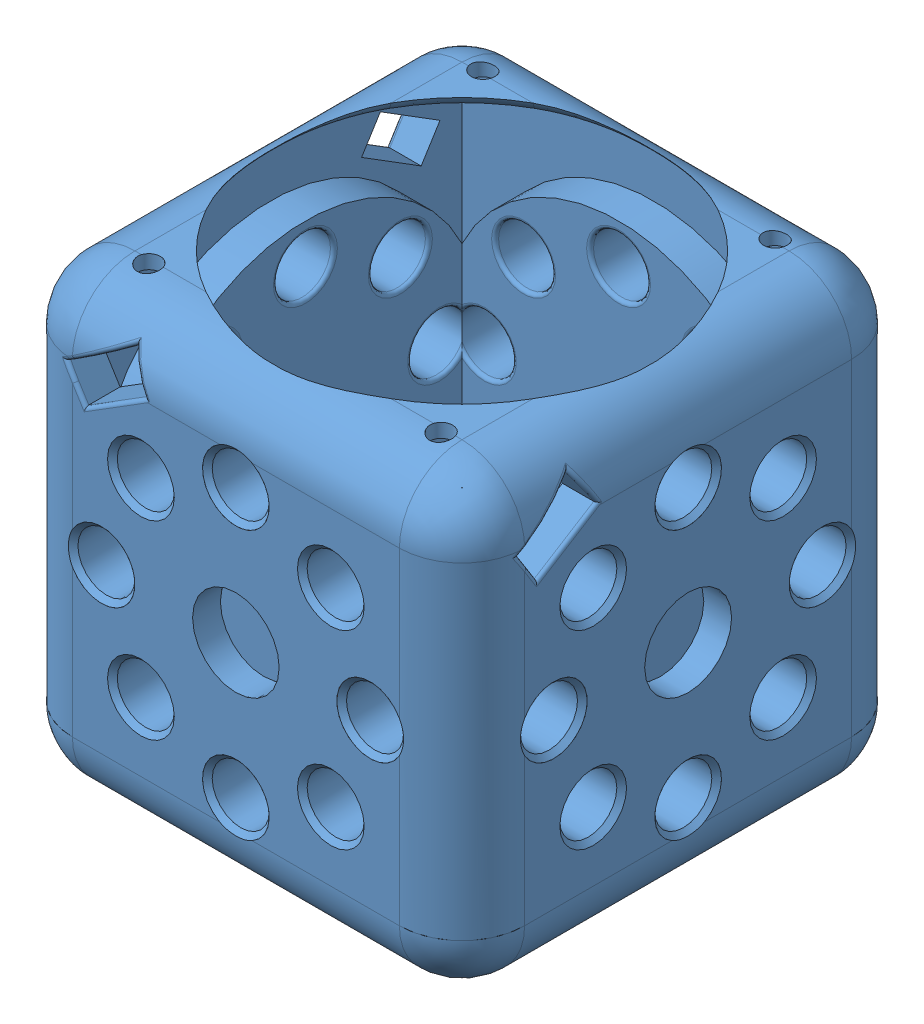
SolidWorks assembly Brick_with_component, configuration Default. Lengths in mm.
Overall size (65.1 65 67.49).
2 component instances, 2 part files, 3 mates.
Components (placement in the parent):
- brick_module-1: brick_module [Default] at (36.7874 45.3941 22.7481) size (65.1 65 67.49)
- 3P Extension PCB-4: 3P Extension PCB [Default] at (16.3785 38.7483 76.0481) x (-1 0 0) z (0 0 -1) size (20 28.2 9.4)
Mates (geometry in assembly coordinates):
- Concentric7: concentric: cylinder of brick_module-1 through (12.3785 50.7483 83.7481) axis (0 0 -1) radius 1.1; cylinder of 3P Extension PCB-4 through (12.3785 50.7483 77.7481) axis (0 0 -1) radius 1
- Concentric8: concentric: cylinder of brick_module-1 through (20.3785 26.7483 83.7481) axis (0 0 -1) radius 1.1; circle of 3P Extension PCB-4
- Coincident5: coincident anti-aligned: plane of brick_module-1 through (16.3785 38.7483 77.7481) normal (0 0 -1); plane of 3P Extension PCB-4 through (16.3785 38.7483 77.7481) normal (0 0 1)
